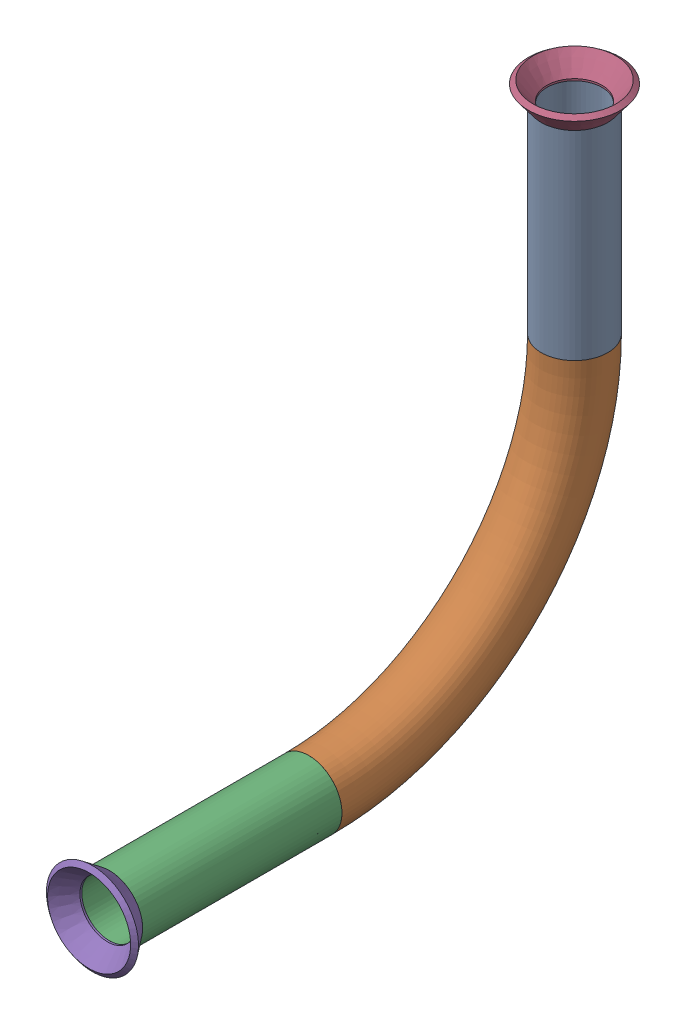
SolidWorks assembly Pipe 33, configuration Default. Lengths in mm.
Overall size (17.59 101.58 101.58).
3 component instances, 2 part files, 3 mates.
Components (placement in the parent):
- Part4-1: Part4 [Default<As Machined>] at origin size (12.7 95.25 95.25)
- Flared pipe end - .5 inch-2: Flared pipe end - .5 inch [Default<As Machined>] at (0 -127.0739 192.4291) x (0 0 1) z (0 1 0) size (17.59 17.59 3.89)
- Flared pipe end - .5 inch-3: Flared pipe end - .5 inch [Default<As Machined>] at (0 -215.9739 281.3291) x (0 -1 0) z (0 0 1) size (17.59 17.59 3.89)
Mates (geometry in assembly coordinates):
- Coincident1693: coincident: circle of Part4-1; circle of Flared pipe end - .5 inch-2
- Coincident1707: coincident: plane of Part4-1 through (0 -215.9739 281.3291) normal (0 0 1); plane of Flared pipe end - .5 inch-3 through (5.2832 -215.9739 281.3291) normal (0 0 -1)
- Coincident1708: coincident: circle of Part4-1; circle of Flared pipe end - .5 inch-3
